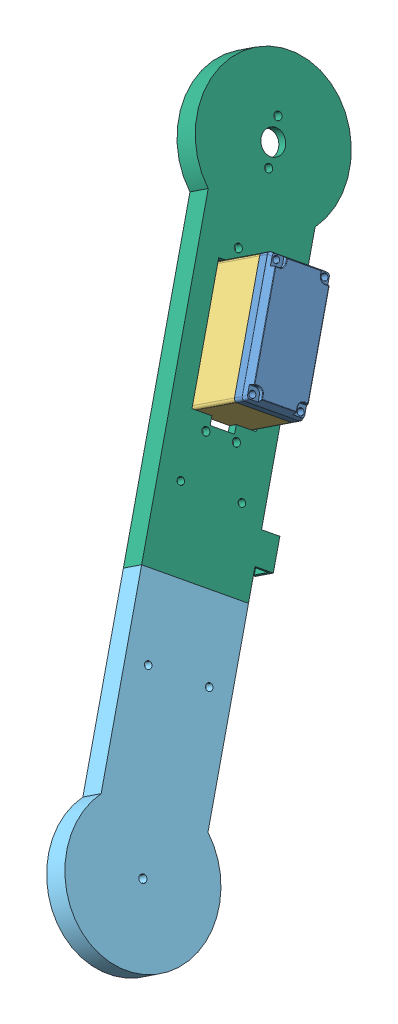
SolidWorks assembly Złożenie3, configuration Domyślna. Lengths in mm.
Overall size (128.8 189.44 201.48).
8 component instances, 7 part files, 10 mates.
Components (placement in the parent):
- MG_996R-1: MG_996R [Domyślna] at (112.7095 -80.9773 116.6892) x (-0.360669 0.546439 0.755859) z (-0.416374 0.630837 -0.654735) size (19.93 44.4 54.6)
  - Base-1: Base [Domyślna] at (12.6939 -23.8049 -20.4733) size (19.93 6.4 40.73)
  - Eje-1: Eje [Domyślna] at (12.6939 -50.7049 -30.7733) x (-0.837169 0 -0.546944) z (-0.546944 0 0.837169) size (5.78 17.5 5.8)
  - Medio-1: Medio [Domyślna] at (12.6939 -30.2049 -20.4733) size (19.8 20.5 40.6)
  - Top-1: Top [Domyślna] at (12.6939 -59.7049 -20.4733) x (-1 0 0) z (0 0 1) size (19.8 13.2 54.6) (hidden)
- plytka-1: plytka [Domyślna] at (97.1707 -158.5581 182.1546) x (-0.360669 0.546439 0.755859) z (0.834596 0.550863 0) size (28.8 60 5)
- ramie1-1: ramie1 [Domyślna] at (47.2058 -82.8576 103.5865) x (0.416374 -0.630837 0.654735) z (0.834596 0.550863 0) size (232.1 50 8)
- ramie-1: ramie [Domyślna] at (47.2058 -82.8576 103.5865) x (0.416374 -0.630837 0.654735) z (0.834596 0.550863 0) size (145 50 8)
Mates (geometry in assembly coordinates):
- Koncentryczne254: concentric aligned: cylinder of MG_996R-1/Top-1 through (80.561 -129.3994 159.7642) axis (0.834596 0.550863 0) radius 2.2; cylinder of ramie-1 through (85.4017 -126.2044 159.7642) axis (0.834596 0.550863 0) radius 1.3
- Koncentryczne255: concentric anti-aligned: cylinder of ramie-1 through (89.0083 -131.6688 152.2056) axis (0.834596 0.550863 0) radius 1.3; cylinder of MG_996R-1/Top-1 through (84.1677 -134.8638 152.2056) axis (-0.834596 -0.550863 0) radius 2.2
- Wspólnie236: coincident anti-aligned: plane of ramie-1 through (51.3788 -80.1033 103.5865) normal (-0.834596 -0.550863 0); plane of MG_996R-1/Top-1 through (74.3377 -114.8877 139.6885) normal (0.834596 0.550863 0)
- Koncentryczne250: concentric anti-aligned: cylinder of ramie-1 through (87.3277 -134.5684 173.3449) axis (-0.834596 -0.550863 0) radius 1.2; cylinder of plytka-1 through (87.3277 -134.5684 173.3449) axis (0.834596 0.550863 0) radius 1.3
- Wspólnie234: coincident anti-aligned: plane of ramie-1 through (51.3788 -80.1033 103.5865) normal (-0.834596 -0.550863 0); plane of plytka-1 through (101.3437 -155.8037 182.1546) normal (0.834596 0.550863 0)
- Koncentryczne251: concentric anti-aligned: cylinder of ramie1-1 through (108.1464 -166.1103 206.0816) axis (-0.834596 -0.550863 0) radius 1.2; cylinder of plytka-1 through (108.1464 -166.1103 206.0816) axis (0.834596 0.550863 0) radius 1.3
- Wspólnie231: coincident anti-aligned: plane of ramie-1 through (97.1707 -158.5581 182.1546) normal (0.416374 -0.630837 0.654735); plane of ramie1-1 through (97.1707 -158.5581 182.1546) normal (-0.416374 0.630837 -0.654735)
- Wspólnie232: coincident aligned: plane of ramie-1 through (55.0046 -80.1507 128.5034) normal (-0.360669 0.546439 0.755859); plane of ramie1-1 through (55.0046 -80.1507 128.5034) normal (-0.360669 0.546439 0.755859)
- Wspólnie233: coincident aligned: plane of ramie-1 through (53.8826 -78.4507 103.5865) normal (0.834596 0.550863 0); plane of ramie1-1 through (53.8826 -78.4507 103.5865) normal (0.834596 0.550863 0)
- Wspólnie183: coincident aligned: plane of ramie-1 through (53.8826 -78.4507 103.5865) normal (0.834596 0.550863 0); plane of ramie1-1 through (53.8826 -78.4507 103.5865) normal (0.834596 0.550863 0)
